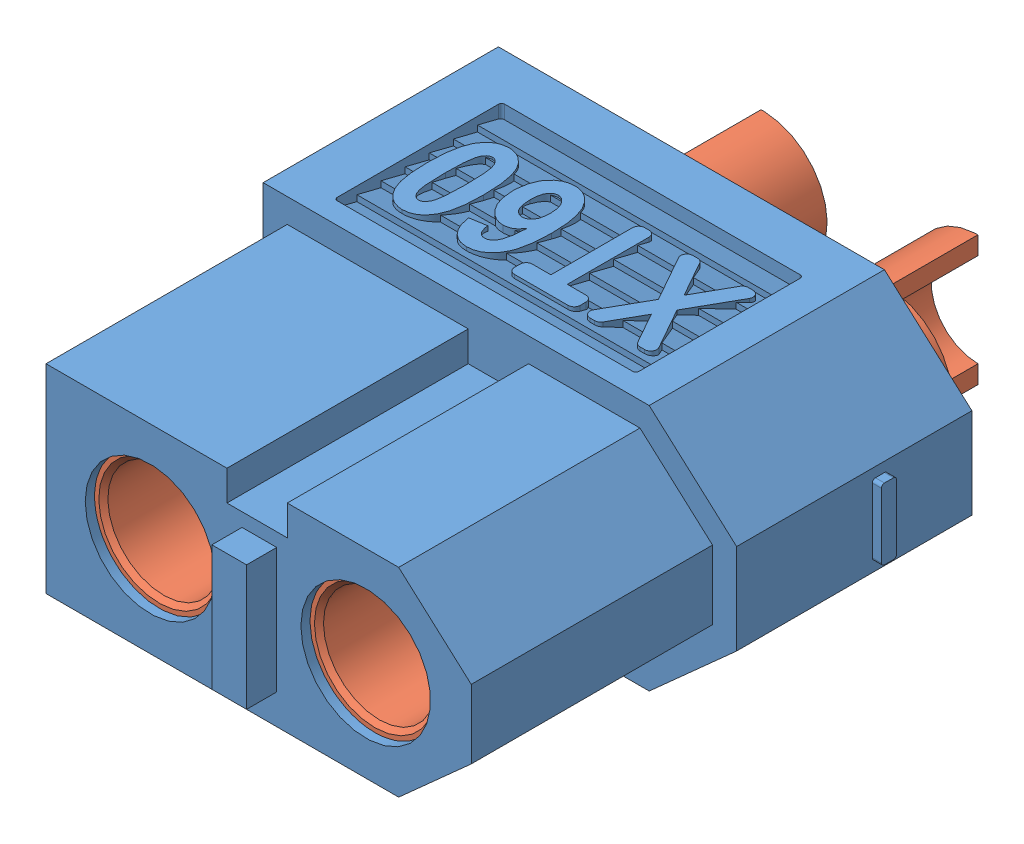
SolidWorks assembly XT-60_Femea, configuration Valor predeterminado. Lengths in mm.
Overall size (16.3 8.2 28.3).
3 component instances, 2 part files, 4 mates.
Components (placement in the parent):
- XT-60_Femea-1: XT-60_Femea [Valor predeterminado] at (-45.4071 14.4296 -8.6) size (16.3 8.2 16.8)
- PinoXT-60_Femea-1: PinoXT-60_Femea [Valor predeterminado] at (-41.1571 18.5296 -13.1) x (0.019097 -0.999818 0) z (-0.999818 -0.019097 0) size (4.3 27 4.3)
- PinoXT-60_Femea-2: PinoXT-60_Femea [Valor predeterminado] at (-34.0071 18.5296 -13.1) x (-0.00106 0.999999 0) z (0.999999 0.00106 0) size (4.3 27 4.3)
Mates (geometry in assembly coordinates):
- Concêntrico1: concentric aligned: cylinder of XT-60_Femea-1 through (-41.1571 18.5296 7.2) axis (0 0 -1) radius 2.15; cylinder of PinoXT-60_Femea-1 through (-41.1571 18.5296 -9.1) axis (0 0 -1) radius 2.15
- Concêntrico2: concentric aligned: cylinder of XT-60_Femea-1 through (-34.0071 18.5296 7.2) axis (0 0 -1) radius 2.15; cylinder of PinoXT-60_Femea-2 through (-34.0071 18.5296 -9.1) axis (0 0 -1) radius 2.15
- Distância1: distance = 0.3 mm: plane of PinoXT-60_Femea-1 through (-41.116 16.38 6.9) normal (0 0 1); plane of XT-60_Femea-1 through (-45.4071 14.4296 7.2) normal (0 0 1)
- Distância2: distance = 0.3 mm aligned: plane of PinoXT-60_Femea-2 through (-34.0094 20.6796 6.9) normal (0 0 1); plane of XT-60_Femea-1 through (-45.4071 14.4296 7.2) normal (0 0 1)
